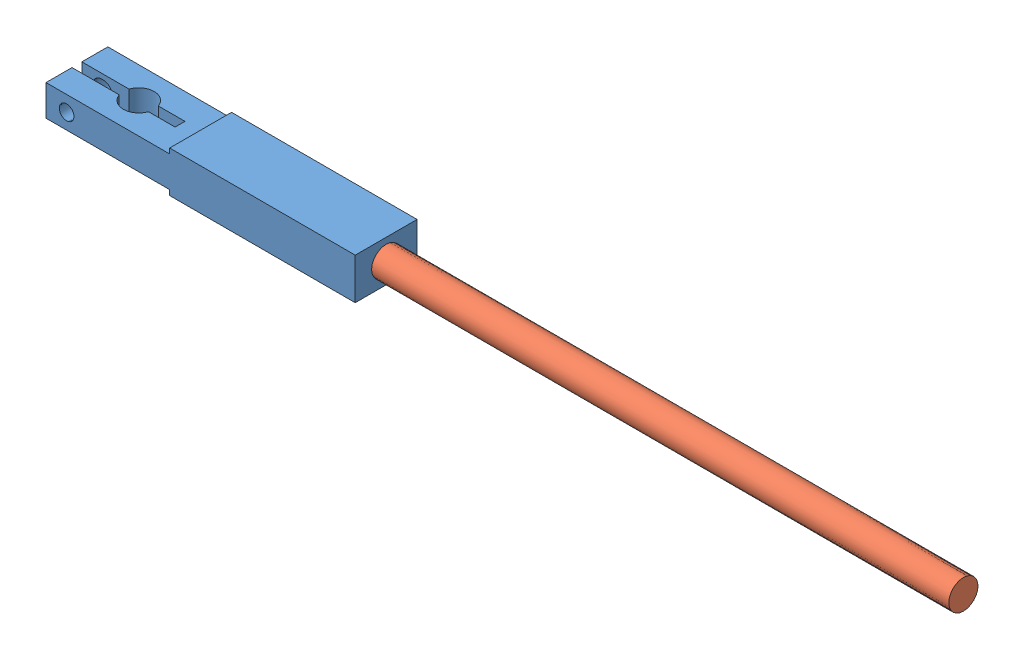
SolidWorks assembly spring-drive-arm-asm, configuration Default. Lengths in mm.
Overall size (136.53 6.35 9.53).
2 component instances, 2 part files, 2 mates.
Components (placement in the parent):
- a17-spring-shaft-drive-1: a17-spring-shaft-drive [Default] at origin size (47.62 6.35 9.53)
- a18-threaded-rod-2: a18-threaded-rod [Default] at (25.4 0 0) x (0 0 -1) z (1 0 0) size (4.5 4.5 101.6)
Mates (geometry in assembly coordinates):
- Concentric1: concentric anti-aligned: cylinder of a17-spring-shaft-drive-1; unknown of a18-threaded-rod-2
- Distance1: distance = 12.7 mm anti-aligned: plane of a17-spring-shaft-drive-1 through (38.1 3.175 -4.7625) normal (1 0 0); unknown of a18-threaded-rod-2
